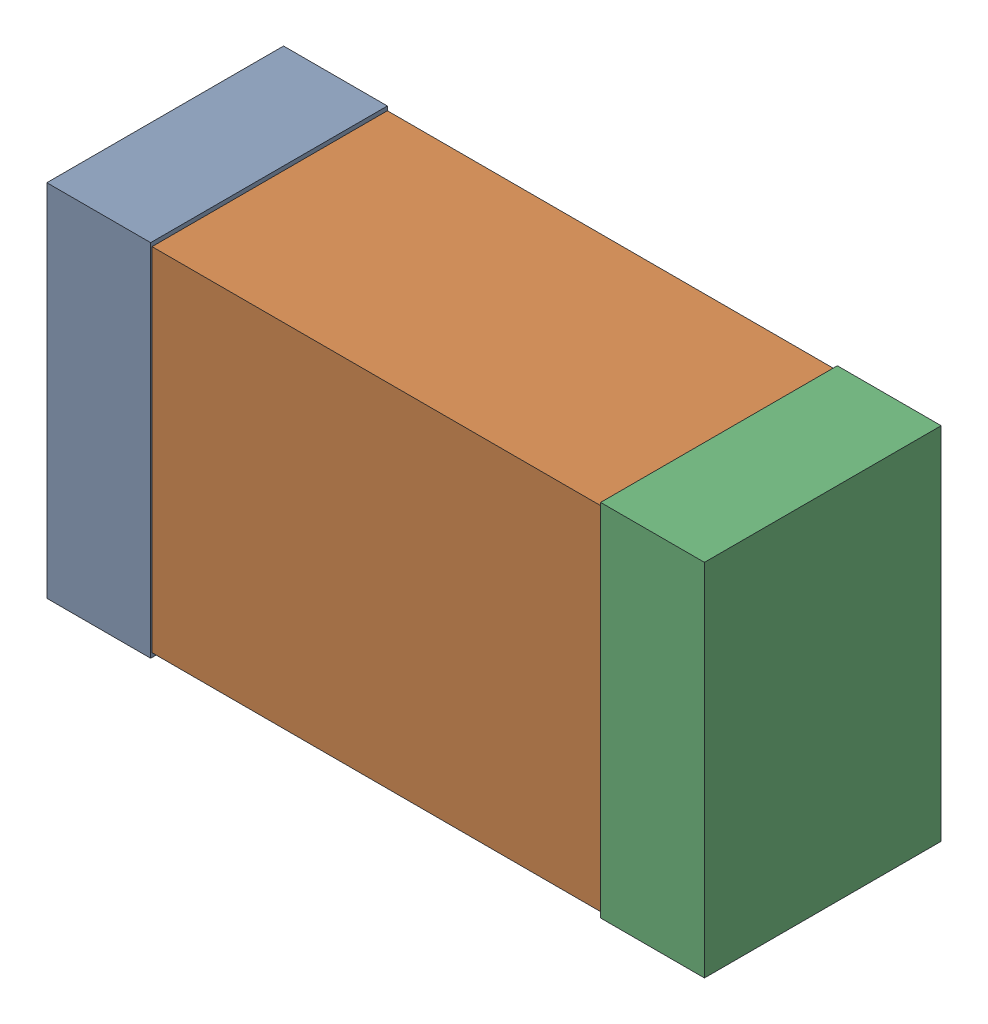
SolidWorks assembly C4Kanaloa_v2.0.0_Power, configuration Default. Lengths in mm.
Overall size (2.38 1.3 0.85).
6 component instances, 2 part files, 0 mates.
Components (placement in the parent):
- 352877648-1: 352877648 [Default] at (69.5 112.275 0) size (0.38 1.3 0.85)
  - Extruded_14-1: Extruded_14 [Default] at origin size (0.38 1.3 0.85)
- 352877904-1: 352877904 [Default] at (70.5 112.275 0) size (2.2 1.27 0.85)
  - Extruded_18-1: Extruded_18 [Default] at origin size (2.2 1.27 0.85)
- 352877648-2: 352877648 [Default] at (71.5 112.275 0) size (0.38 1.3 0.85)
  - Extruded_14-1: Extruded_14 [Default] at origin size (0.38 1.3 0.85)
